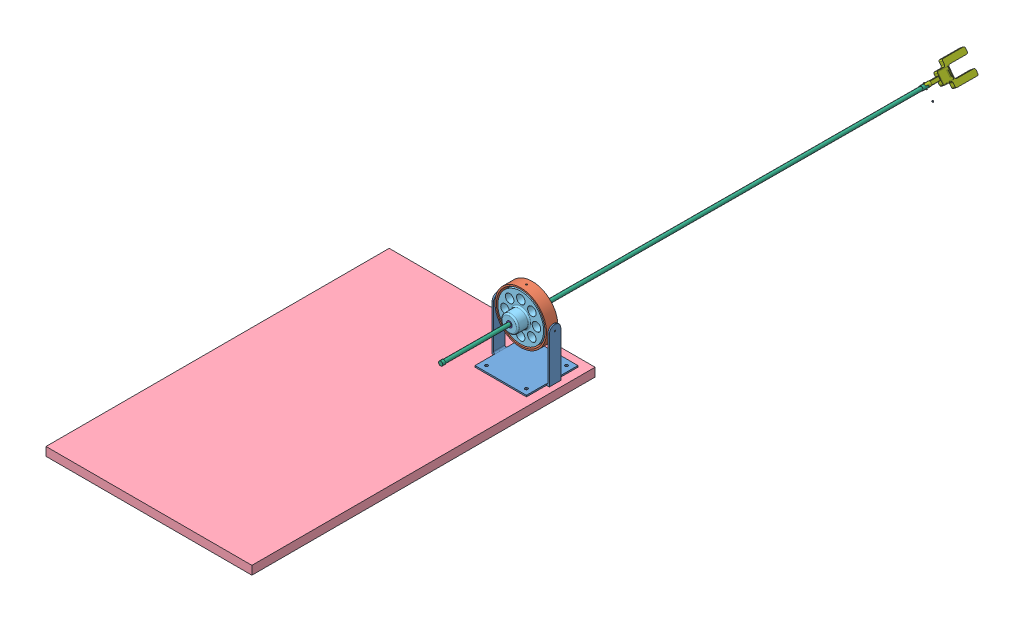
SolidWorks assembly gimbal_assist, configuration Default. Lengths in mm.
Overall size (1828.8 711.41 6680.54).
18 component instances, 11 part files, 36 mates.
Components (placement in the parent):
- gimbal platform-1: gimbal platform [Default] at origin size (508 457.2 457.2)
- outer ring-1: outer ring [Default] at (0 406.6125 -177.8004) x (0 -0.999991 0.004184) z (0 -0.004184 -0.999991) size (457.2 457.2 101.6)
- ring_pin-1: ring_pin [Default] at (254 406.4 -228.6) x (0 -0.924225 -0.381849) z (-1 0 0) size (12.7 12.7 38.1)
- ring_pin-2: ring_pin [Default] at (-215.9 406.4 -228.6) x (0 0 1) z (-1 0 0) size (12.7 12.7 38.1)
- Platform-1: Platform [Default] at (-1524 -76.2 -533.4) x (0 0 1) z (-1 0 0) size (3048 76.2 1828.8)
- inner ring-1: inner ring [Default] at (0 405.711 -279.3976) x (-1 0 0) z (0 0.004184 0.999991) size (406.4 406.4 304.8)
- hot stick-1: hot stick [Default] at (0 391.259 -3733.7673) x (0 0.004184 0.999991) z (-0.611554 0.791196 -0.00331) size (4318 38.1 38.1)
- SensorLink-1: SensorLink [Default] at (-43.9017 416.2692 -3886.2733) x (0.611554 -0.791196 0.00331) z (0.791203 0.611548 -0.002559) size (203.2 406.4 38.1)
- ring_pin-3: ring_pin [Default] at (0 634.998 -229.5564) x (0.866258 0.00209 0.499593) z (0 -0.999991 0.004184) size (12.7 12.7 38.1)
- ring_pin-4: ring_pin [Default] at (0 215.9017 -227.803) x (0.089093 0.004167 0.996015) z (0 -0.999991 0.004184) size (12.7 12.7 38.1)
- hotstick sleeve-1: hotstick sleeve [Default] at (0 405.711 -279.3976) x (-0.687163 -0.726497 0.003039) z (0 -0.004184 -0.999991) size (50.8 50.8 101.6)
- hotstick sleeve-2: hotstick sleeve [Default] at (0 406.1361 -177.7985) x (-0.730686 0.682707 -0.002856) z (0 0.004184 0.999991) size (50.8 50.8 101.6)
- binding head screw_ai-1: binding head screw_ai [SL-BHMS 0.25-28x1.75x1-N] at (-14.2131 409.4878 -3771.9439) x (0.611554 -0.791196 0.00331) z (-0.079671 -0.057418 0.995166) size (48.61 13.33 13.33)
- acorn low crown nut_ai-1: acorn low crown nut_ai [ALCNUT 0.2500-28-N] at (62.9949 309.6001 -3771.526) x (0.611554 -0.791196 0.00331) z (-0.049912 -0.034404 0.998161) size (11.94 12.83 11.11)
- gimbal spacer-1: gimbal spacer [Default] at (0 609.1218 -229.4481) x (1 0 0) z (0 0.999991 -0.004184) size (25.4 25.4 12.7)
- gimbal spacer-2: gimbal spacer [Default] at (0 190.0254 -227.6948) x (1 0 0) z (0 0.999991 -0.004184) size (25.4 25.4 12.7)
- gimbal spacer-3: gimbal spacer [Default] at (-228.6 406.4 -228.6) x (0 0 1) z (-1 0 0) size (25.4 25.4 12.7)
- gimbal spacer-4: gimbal spacer [Default] at (241.3 406.4 -228.6) x (0 0 1) z (-1 0 0) size (25.4 25.4 12.7)
Mates (geometry in assembly coordinates):
- Concentric1: concentric anti-aligned: circle of gimbal platform-1; cylinder of ring_pin-1 through (215.9 406.4 -228.6) axis (1 0 0) radius 6.35
- Coincident4: coincident aligned: plane of gimbal platform-1 through (254 457.2 -177.8) normal (1 0 0); plane of ring_pin-1 through (254 406.4 -228.6) normal (1 0 0)
- Concentric2: concentric anti-aligned: cylinder of outer ring-1 through (228.6 406.4 -228.6) axis (-1 0 0) radius 6.35; cylinder of ring_pin-1 through (215.9 406.4 -228.6) axis (1 0 0) radius 6.35
- Tangent1: tangent anti-aligned: cylinder of outer ring-1 through (0 406.6125 -177.8004) axis (0 -0.004184 -0.999991) radius 215.9; plane of ring_pin-1 through (215.9 406.4 -228.6) normal (-1 0 0)
- Concentric4: concentric anti-aligned: cylinder of gimbal platform-1 through (254 406.4 -228.6) axis (-1 0 0) radius 6.35; cylinder of ring_pin-2 through (-254 406.4 -228.6) axis (1 0 0) radius 6.35
- Coincident5: coincident aligned: plane of gimbal platform-1 through (-254 457.2 -177.8) normal (-1 0 0); plane of ring_pin-2 through (-254 406.4 -228.6) normal (-1 0 0)
- Coincident6: coincident anti-aligned: plane of gimbal platform-1 through (0 0 -457.2) normal (0 -1 0); plane of Platform-1 through (304.8 0 -533.4) normal (0 1 0)
- Concentric6: concentric aligned: cylinder of gimbal platform-1 through (-177.8 0 -50.8) axis (0 1 0) radius 12.7; cylinder of Platform-1 through (-177.8 -76.2 -50.8) axis (0 1 0) radius 12.7
- Concentric8: concentric: cylinder of outer ring-1 through (0 431.323 -184.334) axis (0 -0.490611 -0.871379) radius 215.9; cylinder of inner ring-1 through (0 431.323 -184.334) axis (0 -0.490611 -0.871379) radius 215.9
- Coincident8: coincident: plane of outer ring-1; plane of inner ring-1
- Concentric10: concentric anti-aligned: cylinder of inner ring-1 through (0 405.286 -380.9967) axis (0 0.004184 0.999991) radius 19.05; cylinder of hot stick-1 through (0 409.1115 533.3953) axis (0 -0.004184 -0.999991) radius 15.875
- Distance1: distance = 609.6 mm aligned: plane of hot stick-1 through (0 409.1115 533.3953) normal (0 0.004184 0.999991); plane of inner ring-1 through (0 406.5611 -76.1993) normal (0 0.004184 0.999991)
- Coincident11: coincident anti-aligned: plane of hot stick-1 through (20.9889 407.3758 -3759.235) normal (-0.611554 0.791196 -0.00331); plane of SensorLink-1 through (21.0746 407.3357 -3784.635) normal (0.611554 -0.791196 0.00331)
- Concentric11: concentric aligned: cylinder of hot stick-1 through (0 409.1115 533.3953) axis (0 -0.004184 -0.999991) radius 15.875; cylinder of SensorLink-1 through (0 391.1527 -3759.1671) axis (0 -0.004184 -0.999991) radius 19.05
- Coincident12: coincident anti-aligned: circle of hot stick-1; plane of SensorLink-1 through (0 391.1527 -3759.1671) normal (0 0.004184 0.999991)
- Concentric12: concentric aligned: cylinder of outer ring-1 through (0 634.998 -229.5564) axis (0 -0.999991 0.004184) radius 6.35; cylinder of inner ring-1 through (0 609.1228 -229.4481) axis (0 -0.999991 0.004184) radius 6.35
- Concentric13: concentric anti-aligned: cylinder of outer ring-1 through (0 634.998 -229.5564) axis (0 -0.999991 0.004184) radius 6.35; cylinder of ring_pin-3 through (0 596.8983 -229.397) axis (0 0.999991 -0.004184) radius 6.35
- Tangent2: tangent aligned: cylinder of outer ring-1 through (0 406.1875 -279.3996) axis (0 0.004184 0.999991) radius 228.6; plane of ring_pin-3 through (0 634.998 -229.5564) normal (0 0.999991 -0.004184)
- Concentric17: concentric anti-aligned: cylinder of outer ring-1 through (0 634.998 -229.5564) axis (0 -0.999991 0.004184) radius 6.35; cylinder of ring_pin-4 through (0 177.802 -227.6436) axis (0 0.999991 -0.004184) radius 6.35
- Tangent4: tangent aligned: cylinder of outer ring-1 through (0 406.1875 -279.3996) axis (0 0.004184 0.999991) radius 228.6; plane of ring_pin-4 through (0 177.802 -227.6436) normal (0 -0.999991 0.004184)
- Angle1: planar angle = 0 rad aligned: cylinder of outer ring-1 through (0 406.6125 -177.8004) axis (0 -0.004184 -0.999991) radius 215.9; cylinder of inner ring-1 through (0 406.1361 -177.7985) axis (0 -0.004184 -0.999991) radius 203.2
- Concentric18: concentric anti-aligned: cylinder of inner ring-1 through (0 405.286 -380.9967) axis (0 0.004184 0.999991) radius 19.05; cylinder of hotstick sleeve-2 through (0 406.5611 -76.1993) axis (0 -0.004184 -0.999991) radius 19.05
- Coincident13: coincident aligned: plane of inner ring-1 through (0 406.5611 -76.1993) normal (0 0.004184 0.999991); plane of hotstick sleeve-2 through (0 406.5611 -76.1993) normal (0 0.004184 0.999991)
- Concentric19: concentric aligned: cylinder of inner ring-1 through (0 405.286 -380.9967) axis (0 0.004184 0.999991) radius 19.05; cylinder of hotstick sleeve-1 through (0 405.286 -380.9967) axis (0 0.004184 0.999991) radius 19.05
- Coincident14: coincident aligned: plane of inner ring-1 through (0 405.286 -380.9967) normal (0 -0.004184 -0.999991); plane of hotstick sleeve-1 through (0 405.286 -380.9967) normal (0 -0.004184 -0.999991)
- Concentric20: concentric anti-aligned: cylinder of SensorLink-1 through (-59.8962 468.5902 -3772.1912) axis (0.611554 -0.791196 0.00331) radius 6.35; cylinder of binding head screw_ai-1 through (-29.7466 429.5842 -3772.028) axis (-0.611554 0.791196 -0.00331) radius 3.175
- Tangent5: tangent anti-aligned: cylinder of SensorLink-1 through (0 391.1527 -3759.1671) axis (0 -0.004184 -0.999991) radius 19.05; plane of binding head screw_ai-1 through (-9.1508 408.105 -3771.6184) normal (0.611554 -0.791196 0.00331)
- Concentric21: concentric aligned: cylinder of binding head screw_ai-1 through (-29.7466 429.5842 -3772.028) axis (-0.611554 0.791196 -0.00331) radius 3.175; cylinder of acorn low crown nut_ai-1 through (62.9949 309.6001 -3771.526) axis (-0.611554 0.791196 -0.00331) radius 2.7051
- Concentric22: concentric aligned: cylinder of ring_pin-3 through (0 596.8983 -229.397) axis (0 0.999991 -0.004184) radius 6.35; cylinder of gimbal spacer-1 through (0 609.1218 -229.4481) axis (0 0.999991 -0.004184) radius 6.35
- Tangent7: tangent anti-aligned: cylinder of inner ring-1 through (0 406.1361 -177.7985) axis (0 -0.004184 -0.999991) radius 203.2; plane of gimbal spacer-1 through (0 609.1218 -229.4481) normal (0 -0.999991 0.004184)
- Concentric23: concentric anti-aligned: cylinder of ring_pin-2 through (-254 406.4 -228.6) axis (1 0 0) radius 6.35; cylinder of gimbal spacer-3 through (-228.6 406.4 -228.6) axis (-1 0 0) radius 6.35
- Tangent8: tangent anti-aligned: cylinder of outer ring-1 through (0 406.1875 -279.3996) axis (0 0.004184 0.999991) radius 228.6; plane of gimbal spacer-3 through (-228.6 406.4 -228.6) normal (1 0 0)
- Concentric24: concentric aligned: cylinder of ring_pin-4 through (0 177.802 -227.6436) axis (0 0.999991 -0.004184) radius 6.35; cylinder of gimbal spacer-2 through (0 190.0254 -227.6948) axis (0 0.999991 -0.004184) radius 6.35
- Tangent9: tangent anti-aligned: cylinder of inner ring-1 through (0 406.1361 -177.7985) axis (0 -0.004184 -0.999991) radius 203.2; plane of gimbal spacer-2 through (0 202.7253 -227.7479) normal (0 0.999991 -0.004184)
- Concentric25: concentric anti-aligned: cylinder of ring_pin-1 through (215.9 406.4 -228.6) axis (1 0 0) radius 6.35; cylinder of gimbal spacer-4 through (241.3 406.4 -228.6) axis (-1 0 0) radius 6.35
- Tangent10: tangent anti-aligned: cylinder of outer ring-1 through (0 406.1875 -279.3996) axis (0 0.004184 0.999991) radius 228.6; plane of gimbal spacer-4 through (228.6 406.4 -228.6) normal (-1 0 0)
